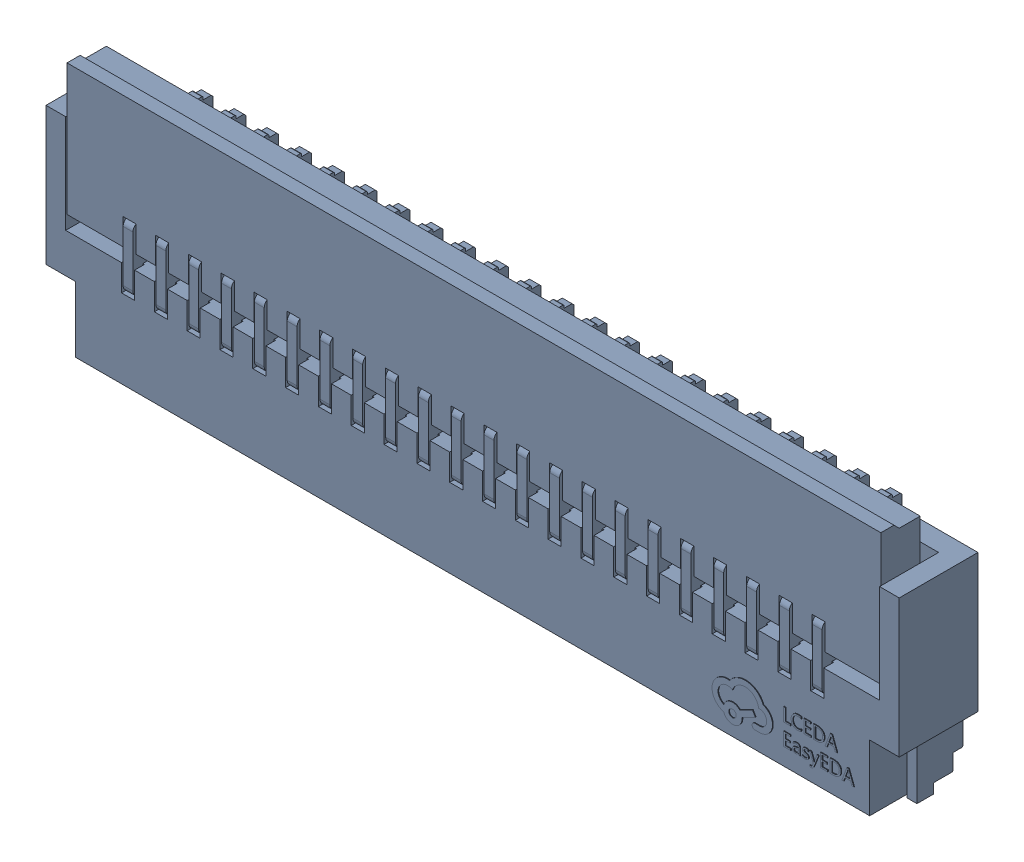
SolidWorks assembly FH34SRJ-22S-0.5SH(50), configuration Défaut. Lengths in mm.
Overall size (13 3.8 1.23).
3 component instances, 1 part files, 0 mates.
Components (placement in the parent):
- FPC1.step_745-1: FPC1.step_745 [Défaut] at (8.84 -9.4501 1.6001) size (13 3.8 1.23)
  - FFC-SMD_22P-P0.50_HRS_FH34SRJ-22S-0.5SH.step-1: FFC-SMD_22P-P0.50_HRS_FH34SRJ-22S-0.5SH.step [Défaut] at origin size (13 3.8 1.23)
    - SOLID.step_747-1: SOLID.step_747 [Défaut] at origin size (13 3.8 1.23)
